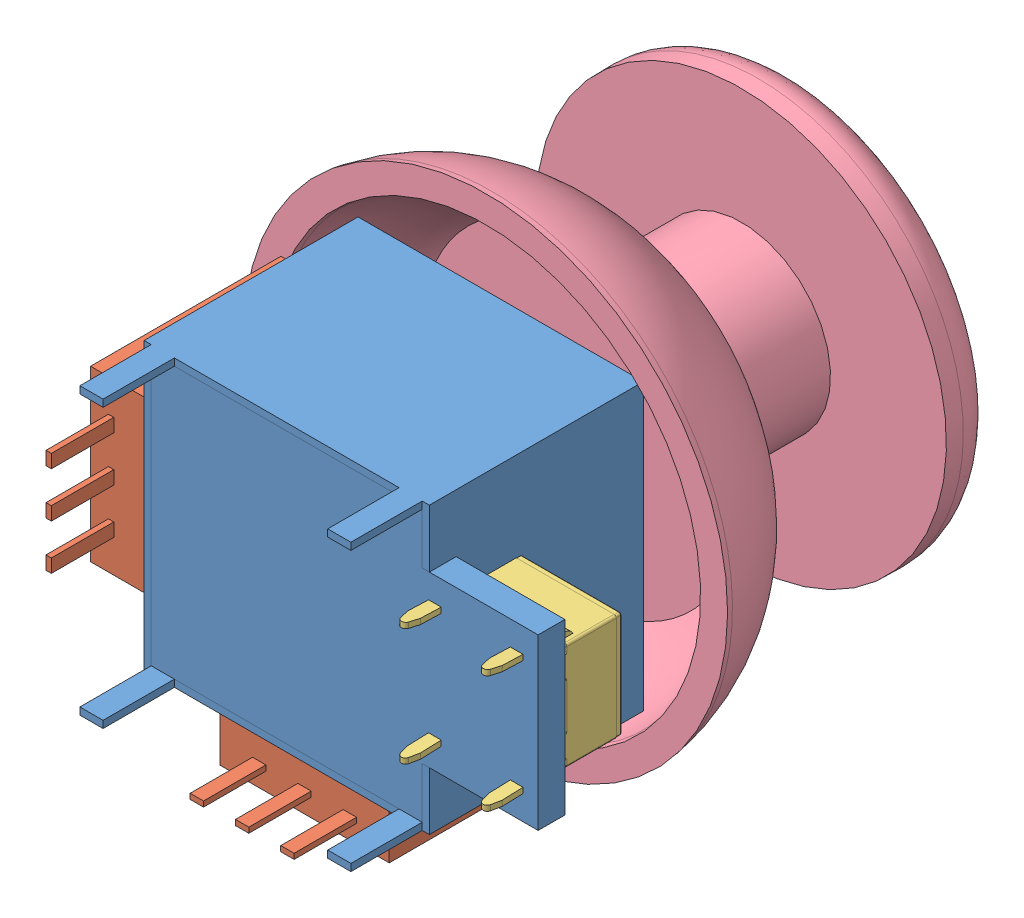
SolidWorks assembly 조이스틱, configuration 기본. Lengths in mm.
Overall size (34.08 34.08 34.52).
5 component instances, 4 part files, 11 mates.
Components (placement in the parent):
- 몸체-1: 몸체 [기본] at (-10.9543 -7.0963 23.5) size (22.1 16 23.5)
- potentiometer-1: potentiometer [기본] at (-2.9543 -7.0963 29) x (-1 0 0) z (0 -1 0) size (9.5 14.5 3.5)
- potentiometer-2: potentiometer [기본] at (-10.9543 0.9037 29.5) x (0 1 0) z (-1 0 0) size (9.5 14.5 3.5)
- tactileswitch-short-1: tactileswitch-short [Default] at (7.6493 0.9037 34) x (0 -1 0) z (1 0 0) size (6.89 8.33 6.01)
- joystickhead-1: joystickhead [기본] at (-8.0303 57.3294 38.75) x (0.304748 -0.952433 0) z (0 0 -1) size (27.11 27.11 19.35)
Mates (geometry in assembly coordinates):
- 일치1: coincident anti-aligned: plane of 몸체-1 through (-10.9543 -7.0963 35.5) normal (0 -1 0); plane of potentiometer-1 through (-2.9543 -7.0963 29) normal (0 1 0)
- 일치2: coincident aligned: plane of 몸체-1 through (-10.9543 -7.0963 23.5) normal (0 0 -1); plane of potentiometer-1 through (1.7957 -10.5963 23.5) normal (0 0 -1)
- 일치3: coincident anti-aligned: plane of potentiometer-1; plane of 몸체-1 through (-2.9543 -7.0963 23.5) normal (1 0 0)
- 일치4: coincident anti-aligned: plane of 몸체-1 through (-10.9543 -7.0963 35.5) normal (-1 0 0); plane of potentiometer-2 through (-10.9543 0.9037 29.5) normal (1 0 0)
- 거리1: distance = 0.5 mm aligned: plane of potentiometer-2 through (-14.4543 -3.8463 24) normal (0 0 -1); plane of 몸체-1 through (-10.9543 -7.0963 23.5) normal (0 0 -1)
- 일치5: coincident anti-aligned: plane of 몸체-1 through (-2.9543 -7.0963 23.5) normal (1 0 0); plane of potentiometer-1
- 일치6: coincident aligned: plane of 몸체-1 through (4.6457 -7.0963 35.5) normal (-1 0 0); plane of tactileswitch-short-1 through (4.6457 3.9073 30.6218) normal (-1 0 0)
- 일치7: coincident anti-aligned: plane of 몸체-1 through (-10.9543 -7.0963 34) normal (0 0 -1); plane of tactileswitch-short-1 through (10.6528 2.2055 34) normal (0 0 1)
- 일치8: coincident anti-aligned: plane of 몸체-1 through (-10.9543 0.9037 23.5) normal (0 1 0); plane of tactileswitch-short-1
- 거리2: distance = 30.5 mm anti-aligned: plane of 몸체-1 through (-10.9543 -7.0963 35.5) normal (0 0 1); plane of joystickhead-1 through (-2.4972 -0.5249 5) normal (0 0 -1)
- 동심1: concentric anti-aligned: cylinder of joystickhead-1 through (-2.9543 0.9037 4.9792) axis (0 0 1) radius 1.6138; line of 몸체-1 through (-2.9543 0.9037 40.3001) axis (0 0 -1)
